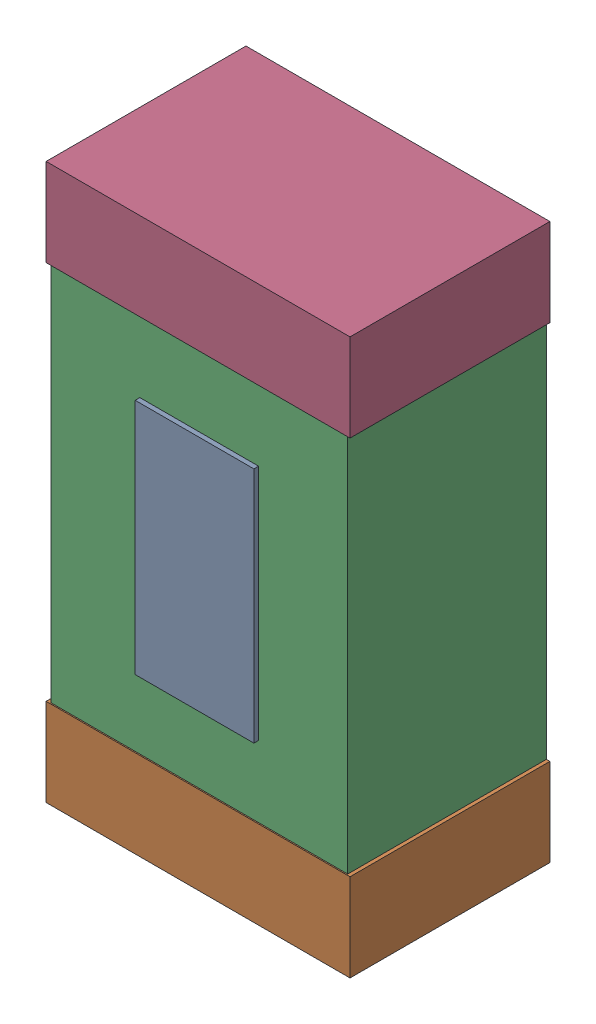
SolidWorks assembly RLEDKanaloa_v2.0.0_Power, configuration Default. Lengths in mm.
Overall size (1.3 2.38 0.87).
8 component instances, 3 part files, 0 mates.
Components (placement in the parent):
- 440440848-1: 440440848 [Default] at (72.35 97.7 0) size (0.51 1.02 0.87)
  - Extruded_4-1: Extruded_4 [Default] at origin size (0.51 1.02 0.87)
- 330415056-1: 330415056 [Default] at (72.35 96.7 0) size (1.3 0.38 0.85)
  - Extruded_2-1: Extruded_2 [Default] at origin size (1.3 0.38 0.85)
- 352877008-1: 352877008 [Default] at (72.35 97.7 0) size (1.27 2.2 0.85)
  - Extruded_3-1: Extruded_3 [Default] at origin size (1.27 2.2 0.85)
- 330415056-2: 330415056 [Default] at (72.35 98.7 0) size (1.3 0.38 0.85)
  - Extruded_2-1: Extruded_2 [Default] at origin size (1.3 0.38 0.85)
